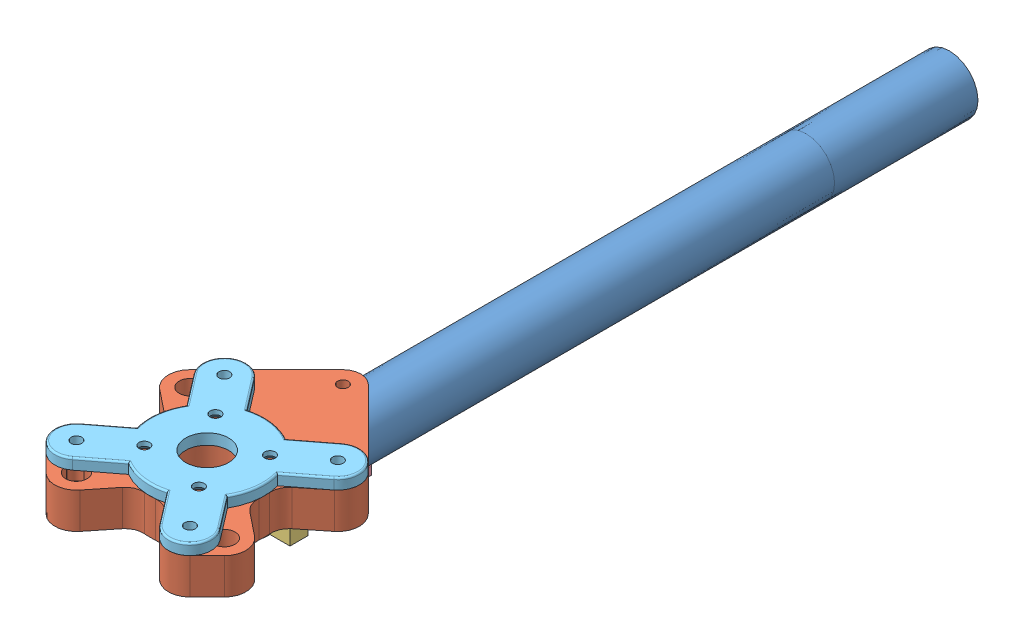
SolidWorks assembly mt6x, configuration Varsayılan. Lengths in mm.
Overall size (91.59 25 251.87).
5 component instances, 5 part files, 10 mates.
Components (placement in the parent):
- boru-1: boru [Varsayılan] at origin size (16 16 200)
- mt-6 x version-1: mt-6 x version [Varsayılan] at (0 2 206.9992) x (0.793353 0 -0.608761) z (0.608761 0 0.793353) size (64 20 67.04)
- Lowerclamp-1: Lowerclamp [Default] at (0 0 192.4992) size (61.76 10 5)
- civata desteği-1: civata desteği [Varsayılan] at (0 0 165.13) size (8 2.68 8)
- motor-x-1: motor-x [Varsayılan] at (0 12 206.9992) x (0.608761 0 0.793353) z (-0.793353 0 0.608761) size (64 3 64)
Mates (geometry in assembly coordinates):
- Concentric15: concentric aligned: cylinder of boru-1 through (0 0 200) axis (0 0 -1) radius 8; cylinder of civata desteği-1 through (0 0 173.13) axis (0 0 -1) radius 8
- Concentric20: concentric aligned: cylinder of mt-6 x version-1 through (-11 2 194.9992) axis (0 1 0) radius 1.5; cylinder of Lowerclamp-1 through (-11 -10 194.9992) axis (0 1 0) radius 1.5
- Concentric27: concentric anti-aligned: cylinder of boru-1 through (0 0 200) axis (0 0 -1) radius 8; cylinder of mt-6 x version-1 through (0 0 159.7168) axis (0 0 1) radius 8
- Concentric28: concentric aligned: cylinder of mt-6 x version-1 through (11 2 194.9992) axis (0 1 0) radius 1.5; cylinder of Lowerclamp-1 through (11 -10 194.9992) axis (0 1 0) radius 1.5
- Concentric29: concentric aligned: cylinder of boru-1 through (0 0 200) axis (0 0 -1) radius 8; cylinder of Lowerclamp-1 through (0 0 197.4992) axis (0 0 -1) radius 8
- Concentric30: concentric anti-aligned: cylinder of boru-1 through (0 -8 169.13) axis (0 1 0) radius 1.5; cylinder of civata desteği-1 through (0 -7.246 169.13) axis (0 -1 0) radius 1.5
- Concentric33: concentric aligned: cylinder of boru-1 through (0 -8 169.13) axis (0 1 0) radius 1.5; cylinder of mt-6 x version-1 through (0 -40.0967 169.13) axis (0 1 0) radius 1.5
- Coincident1: coincident anti-aligned: plane of mt-6 x version-1 through (0 12 206.9992) normal (0 1 0); plane of motor-x-1 through (20.6272 12 191.1714) normal (0 -1 0)
- Concentric34: concentric anti-aligned: cylinder of mt-6 x version-1 through (0 5 206.9992) axis (0 1 0) radius 6.5; cylinder of motor-x-1 through (0 15 206.9992) axis (0 -1 0) radius 6
- Concentric35: concentric aligned: cylinder of mt-6 x version-1 through (20.6272 39.0952 191.1714) axis (0 -1 0) radius 1.75; cylinder of motor-x-1 through (20.6272 15 191.1714) axis (0 -1 0) radius 1.5
